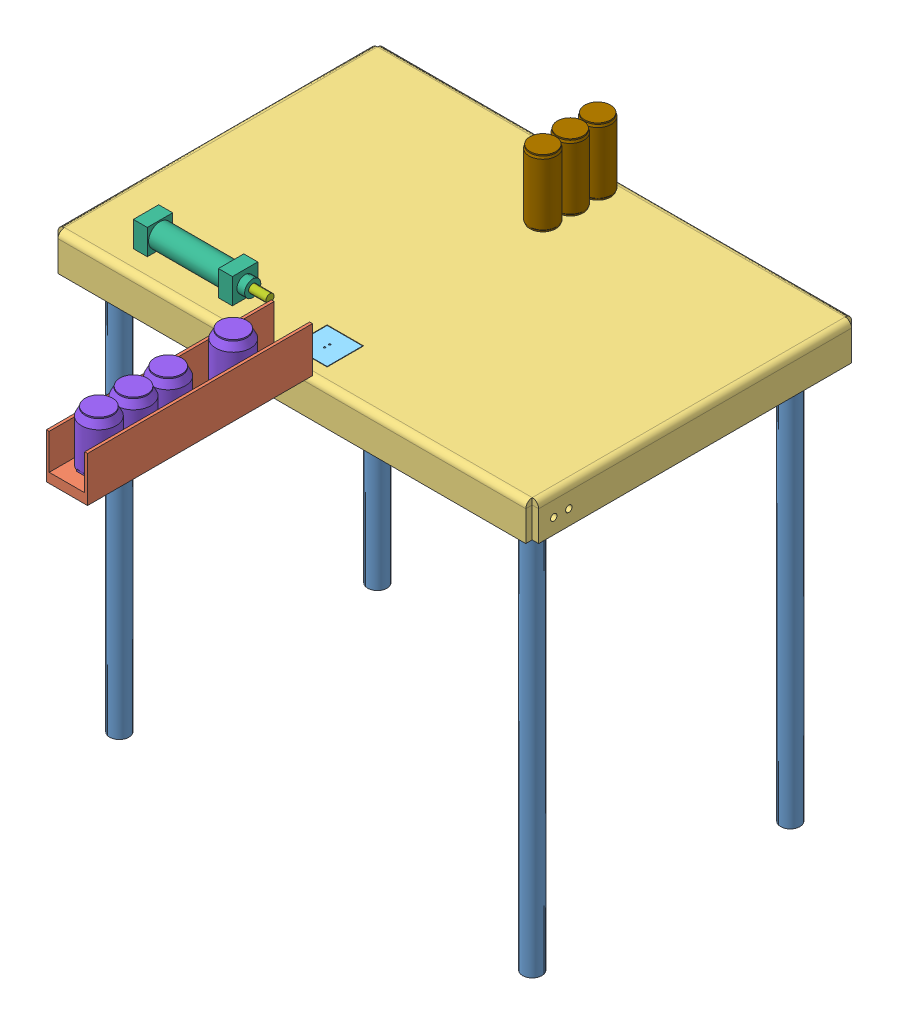
SolidWorks assembly Full_Assembly_v7, configuration Default. Lengths in mm.
Overall size (946.15 1042.06 1084.08).
19 component instances, 12 part files, 63 mates.
Components (placement in the parent):
- M37 Metal Table-1: M37 Metal Table [Default] at (-122.75 340.8931 1031.9817) size (914.4 863.6 609.6)
- Goose Output-1: Goose Output [Default] at (293.9688 417.0931 1047.8567) size (80.96 88.9 442.73)
- Table Topper-1: Table Topper [Default] at (-125.925 340.8931 1035.1567) size (946.15 72.1 641.35)
- Load Cell Assembly-1: Load Cell Assembly [Default] at (309.0555 358.077 899.7114) size (69.85 23.2 103.99)
  - Load Cell and Brace-1: Load Cell and Brace [Default] at (-9.1055 31.7162 92.7424) size (69 14.2 83)
  - scalePlate_v2_234-1: scalePlate_v2_234 [Default] at (-9.5305 54.9162 113.7283) x (0 0 -1) z (-1 0 0) size (69.85 9 69.85)
- Cylinder-1: Cylinder [Default] at (-22.0508 462.9931 953.5147) x (0 0 1) z (1 0 0) size (50 50 210)
- Rod-1: Rod [Default] at (221.9492 437.9931 978.5147) x (0 0.637822 -0.770184) z (0 0.770184 0.637822) size (16 134 16)
- can355mL-1: can355mL [Default] at (334.45 412.9931 1291.3582) x (0 0 -1) z (1 0 0) size (68.26 122.24 68.26)
- can355mL-2: can355mL [Default] at (334.45 412.9931 1427.8832) x (0 0 -1) z (1 0 0) size (68.26 122.24 68.26)
- can355mL-3: can355mL [Default] at (334.45 412.9931 1359.6207) x (0 0 -1) z (1 0 0) size (68.26 122.24 68.26)
- can250mL-1: can250mL [Default] at (334.45 412.9931 553.8493) x (-0.934308 0 -0.356465) z (0.356465 0 -0.934308) size (53.98 131.76 53.98)
- can250mL-2: can250mL [Default] at (334.45 412.9931 499.8743) x (0.439436 0 -0.898274) z (0.898274 0 0.439436) size (53.98 131.76 53.98)
- can250mL-3: can250mL [Default] at (334.45 412.9931 445.8993) x (0.515444 0 0.856923) z (-0.856923 0 0.515444) size (53.98 131.76 53.98)
- can355mL-7: can355mL [Default] at (334.45 412.9931 1163.3587) x (0 0 -1) z (1 0 0) size (68.26 122.24 68.26)
- AmpCase_Assembly_v1-1: AmpCase_Assembly_v1 [Default] at (378.0256 441.5889 898.6464) x (0 0 -1) z (-1 0 0) size (83 107 59)
  - AmpCase_LID_83x59x33_v1-1: AmpCase_LID_83x59x33_v1 [Default] at (42.2994 148.2958 -6.3457) x (1 0 0) z (0 0 -1) size (83 7 59)
  - AmpCase83x59x33_v1-1: AmpCase83x59x33_v1 [Default] at (42.2994 41.2958 52.6543) size (83 26 59)
- Solenoid_v1-1: Solenoid_v1 [Default] at (452.5858 378.2931 857.7853) size (118 22 83)
Mates (geometry in assembly coordinates):
- Width1: width aligned: plane of M37 Metal Table-1 through (791.65 366.2931 1031.9817) normal (1 0 0); plane of M37 Metal Table-1 through (-122.75 366.2931 1031.9817) normal (-1 0 0); plane of Table Topper-1 through (807.525 400.2931 1035.1567) normal (1 0 0); plane of Table Topper-1 through (-138.625 400.2931 1035.1567) normal (-1 0 0)
- Width2: width aligned: plane of M37 Metal Table-1 through (-122.75 366.2931 1031.9817) normal (0 0 1); plane of M37 Metal Table-1 through (-122.75 366.2931 422.3817) normal (0 0 -1); plane of Table Topper-1 through (-125.925 400.2931 1047.8567) normal (0 0 1); plane of Table Topper-1 through (-125.925 400.2931 406.5067) normal (0 0 -1)
- Distance1: distance = 863.6 mm aligned: plane of M37 Metal Table-1 through (-122.75 -446.5069 1031.9817) normal (0 -1 0); plane of Goose Output-1 through (374.9313 417.0931 1490.5914) normal (0 -1 0)
- LimitDistance1: limit distance = 432.5938 mm aligned: plane of Goose Output-1 through (374.9313 505.9931 1490.5914) normal (1 0 0); plane of Table Topper-1 through (807.525 400.2931 1035.1567) normal (1 0 0)
- LimitDistance2: limit distance = 432.5938 mm aligned: plane of Table Topper-1 through (-138.625 400.2931 1035.1567) normal (-1 0 0); plane of Goose Output-1 through (293.9688 417.0931 1490.5914) normal (-1 0 0)
- Parallel1: parallel aligned: plane of Goose Output-1 through (299.525 436.1431 1490.5914) normal (0 1 0); plane of Table Topper-1 through (-125.925 412.9931 1035.1567) normal (0 1 0)
- Coincident7: coincident aligned: plane of Table Topper-1 through (-125.925 412.9931 1035.1567) normal (0 1 0); plane of Load Cell Assembly-1/scalePlate_v2_234-1 through (299.525 412.9931 1013.4397) normal (0 1 0)
- Concentric1: concentric anti-aligned: cylinder of Cylinder-1 through (187.9492 437.9931 978.5147) axis (-1 0 0) radius 16; cylinder of Rod-1 through (87.9492 437.9931 978.5147) axis (1 0 0) radius 8
- LimitDistance3: limit distance = 34 mm aligned: plane of Rod-1 through (221.9492 437.9931 978.5147) normal (1 0 0); plane of Cylinder-1 through (187.9492 437.9931 978.5147) normal (1 0 0)
- Parallel2: parallel anti-aligned: plane of Table Topper-1 through (-125.925 400.2931 1047.8567) normal (0 0 1); plane of Cylinder-1 through (172.9492 462.9931 953.5147) normal (0 0 -1)
- Coincident9: coincident anti-aligned: plane of Table Topper-1 through (-125.925 412.9931 1035.1567) normal (0 1 0); plane of Cylinder-1 through (5.4492 412.9931 953.5147) normal (0 -1 0)
- Width3: width anti-aligned: plane of Goose Output-1 through (374.9313 505.9931 1490.5914) normal (1 0 0); plane of Goose Output-1 through (293.9688 417.0931 1490.5914) normal (-1 0 0); plane of Load Cell Assembly-1/scalePlate_v2_234-1 through (299.525 408.9931 1013.4397) normal (-1 0 0); plane of Load Cell Assembly-1/scalePlate_v2_234-1 through (369.375 408.9931 1013.4397) normal (1 0 0)
- Width4: width anti-aligned: plane of Cylinder-1 through (172.9492 462.9931 953.5147) normal (0 0 -1); plane of Cylinder-1 through (172.9492 462.9931 1003.5147) normal (0 0 1); plane of Load Cell Assembly-1/scalePlate_v2_234-1 through (299.525 408.9931 1013.4397) normal (0 0 1); plane of Load Cell Assembly-1/scalePlate_v2_234-1 through (299.525 408.9931 943.5897) normal (0 0 -1)
- Width5: width anti-aligned: plane of Table Topper-1 through (807.525 400.2931 1035.1567) normal (1 0 0); plane of Table Topper-1 through (-138.625 400.2931 1035.1567) normal (-1 0 0); plane of Load Cell Assembly-1/scalePlate_v2_234-1 through (299.525 408.9931 1013.4397) normal (-1 0 0); plane of Load Cell Assembly-1/scalePlate_v2_234-1 through (369.375 408.9931 1013.4397) normal (1 0 0)
- Coincident11: coincident anti-aligned: plane of Table Topper-1 through (-125.925 412.9931 1035.1567) normal (0 1 0); plane of can250mL-1 through (310.7186 412.9931 544.7951) normal (0 -1 0)
- Coincident18: coincident anti-aligned: plane of Table Topper-1 through (-125.925 412.9931 1035.1567) normal (0 1 0); plane of can355mL-2 through (334.45 412.9931 1400.8957) normal (0 -1 0)
- Coincident19: coincident anti-aligned: plane of Table Topper-1 through (-125.925 412.9931 1035.1567) normal (0 1 0); plane of can355mL-3 through (334.45 412.9931 1332.6332) normal (0 -1 0)
- Tangent5: tangent anti-aligned: cylinder of can355mL-2 through (334.45 412.9931 1427.8832) axis (0 -1 0) radius 34.1313; cylinder of can355mL-3 through (334.45 412.9931 1359.6207) axis (0 -1 0) radius 34.1313
- Width6: width: plane of Goose Output-1 through (299.525 505.9931 1490.5914) normal (1 0 0); plane of Goose Output-1 through (369.375 436.1431 1490.5914) normal (-1 0 0); cylinder of can250mL-1 through (334.45 412.9931 553.8493) axis (0 -1 0) radius 26.9875
- Width8: width: plane of Goose Output-1 through (369.375 436.1431 1490.5914) normal (-1 0 0); plane of Goose Output-1 through (299.525 505.9931 1490.5914) normal (1 0 0); cylinder of can355mL-2 through (334.45 412.9931 1427.8832) axis (0 -1 0) radius 34.1313
- Width10: width: plane of Goose Output-1 through (299.525 505.9931 1490.5914) normal (1 0 0); plane of Goose Output-1 through (369.375 436.1431 1490.5914) normal (-1 0 0); cylinder of can355mL-3 through (334.45 412.9931 1359.6207) axis (0 -1 0) radius 34.1313
- Coincident20: coincident anti-aligned: plane of Table Topper-1 through (-125.925 412.9931 1035.1567) normal (0 1 0); plane of can250mL-2 through (345.6117 412.9931 477.0581) normal (0 -1 0)
- Coincident21: coincident anti-aligned: plane of Table Topper-1 through (-125.925 412.9931 1035.1567) normal (0 1 0); plane of can250mL-3 through (347.5423 412.9931 467.6651) normal (0 -1 0)
- Tangent6: tangent anti-aligned: cylinder of can250mL-1 through (334.45 412.9931 553.8493) axis (0 -1 0) radius 26.9875; cylinder of can250mL-2 through (334.45 412.9931 499.8743) axis (0 -1 0) radius 26.9875
- Tangent7: tangent anti-aligned: cylinder of can250mL-2 through (334.45 412.9931 499.8743) axis (0 -1 0) radius 26.9875; cylinder of can250mL-3 through (334.45 412.9931 445.8993) axis (0 -1 0) radius 26.9875
- Width11: width: plane of Goose Output-1 through (299.525 505.9931 1490.5914) normal (1 0 0); plane of Goose Output-1 through (369.375 436.1431 1490.5914) normal (-1 0 0); cylinder of can250mL-2 through (334.45 412.9931 499.8743) axis (0 -1 0) radius 26.9875
- Width12: width: plane of Goose Output-1 through (299.525 505.9931 1490.5914) normal (1 0 0); plane of Goose Output-1 through (369.375 436.1431 1490.5914) normal (-1 0 0); cylinder of can250mL-3 through (334.45 412.9931 445.8993) axis (0 -1 0) radius 26.9875
- Coincident22: coincident anti-aligned: plane of Goose Output-1 through (293.9688 417.0931 1047.8567) normal (0 0 -1); plane of Table Topper-1 through (-125.925 400.2931 1047.8567) normal (0 0 1)
- Width14: width aligned: plane of Table Topper-1 through (370.391 340.8931 1014.4557) normal (-1 0 0); plane of Load Cell Assembly-1/scalePlate_v2_234-1 through (298.509 340.8931 1014.4557) normal (1 0 0); plane of Table Topper-1 through (299.525 408.9931 1013.4397) normal (-1 0 0); plane of Load Cell Assembly-1/scalePlate_v2_234-1 through (369.375 408.9931 1013.4397) normal (1 0 0)
- Width15: width anti-aligned: plane of Table Topper-1 through (298.509 340.8931 1014.4557) normal (0 0 -1); plane of Load Cell Assembly-1/scalePlate_v2_234-1 through (298.509 340.8931 942.5737) normal (0 0 1); plane of Table Topper-1 through (299.525 408.9931 1013.4397) normal (0 0 1); plane of Load Cell Assembly-1/scalePlate_v2_234-1 through (299.525 408.9931 943.5897) normal (0 0 -1)
- Width17: width: plane of Goose Output-1 through (369.375 436.1431 1490.5914) normal (-1 0 0); plane of can355mL-4 through (299.525 505.9931 1490.5914) normal (1 0 0); cylinder of Goose Output-1 through (334.45 436.1431 1259.8293) axis (0 -1 0) radius 34.1313
- Coincident31: coincident anti-aligned: plane of Table Topper-1 through (-125.925 412.9931 1035.1567) normal (0 1 0); plane of can355mL-7 through (334.45 412.9931 1136.3712) normal (0 -1 0)
- Width19: width: plane of Goose Output-1 through (369.375 436.1431 1490.5914) normal (-1 0 0); plane of can355mL-7 through (299.525 505.9931 1490.5914) normal (1 0 0); cylinder of Goose Output-1 through (334.45 412.9931 1163.3587) axis (0 -1 0) radius 34.1313
- Coincident33: coincident anti-aligned: plane of Table Topper-1 through (-125.925 412.9931 1035.1567) normal (0 1 0); plane of can355mL-1 through (334.45 412.9931 1264.3707) normal (0 -1 0)
- Tangent13: tangent anti-aligned: cylinder of can355mL-1 through (334.45 412.9931 1291.3582) axis (0 -1 0) radius 34.1313; cylinder of can355mL-3 through (334.45 412.9931 1359.6207) axis (0 -1 0) radius 34.1313
- Width20: width: plane of Goose Output-1 through (299.525 505.9931 1490.5914) normal (1 0 0); plane of can355mL-1 through (369.375 436.1431 1490.5914) normal (-1 0 0); cylinder of Goose Output-1 through (334.45 412.9931 1291.3582) axis (0 -1 0) radius 34.1313
- Parallel4: parallel aligned: plane of M37 Metal Table-1 through (-122.75 366.2931 1031.9817) normal (0 0 1); plane of can355mL-7 through (334.45 412.9931 1197.4899) normal (0 0 1)
- Parallel5: parallel aligned: plane of M37 Metal Table-1 through (-122.75 366.2931 1031.9817) normal (0 0 1); plane of can355mL-2 through (334.45 412.9931 1462.0144) normal (0 0 1)
- Parallel6: parallel aligned: plane of M37 Metal Table-1 through (-122.75 366.2931 1031.9817) normal (0 0 1); plane of can355mL-3 through (334.45 412.9931 1393.7519) normal (0 0 1)
- Parallel7: parallel aligned: plane of M37 Metal Table-1 through (-122.75 366.2931 1031.9817) normal (0 0 1); plane of can355mL-1 through (334.45 412.9931 1325.4894) normal (0 0 1)
- LimitDistance14: limit distance = 127.9995 mm aligned: plane of can355mL-7 through (334.45 412.9931 1197.4899) normal (0 0 1); plane of can355mL-1 through (334.45 412.9931 1325.4894) normal (0 0 1)
- Tangent14: tangent anti-aligned: cylinder of can355mL-9 through (334.45 412.9931 1319.9352) axis (0 -1 0) radius 34.1313; cylinder of can355mL-10 through (334.45 412.9931 1388.1977) axis (0 -1 0) radius 34.1313
- Tangent15: tangent anti-aligned: cylinder of can355mL-8 through (334.45 412.9931 1456.4602) axis (0 -1 0) radius 34.1313; cylinder of can355mL-10 through (334.45 412.9931 1388.1977) axis (0 -1 0) radius 34.1313
- Coincident38: coincident anti-aligned: plane of Table Topper-1 through (-125.925 412.9931 1035.1567) normal (0 1 0); plane of can355mL-8 through (334.45 412.9931 1429.4727) normal (0 -1 0)
- Coincident39: coincident aligned: plane of can355mL-9 through (334.45 412.9931 1292.9477) normal (0 -1 0); plane of can355mL-10 through (334.45 412.9931 1361.2102) normal (0 -1 0)
- Coincident40: coincident anti-aligned: plane of Table Topper-1 through (-125.925 412.9931 1035.1567) normal (0 1 0); plane of can355mL-10 through (334.45 412.9931 1361.2102) normal (0 -1 0)
- Width21: width: plane of Goose Output-1 through (299.525 505.9931 1490.5914) normal (1 0 0); plane of Goose Output-1 through (369.375 436.1431 1490.5914) normal (-1 0 0); cylinder of can355mL-8 through (334.45 412.9931 1456.4602) axis (0 -1 0) radius 34.1313
- Width22: width: plane of Goose Output-1 through (374.9313 505.9931 1490.5914) normal (1 0 0); plane of Goose Output-1 through (293.9688 417.0931 1490.5914) normal (-1 0 0); cylinder of can355mL-10 through (334.45 412.9931 1388.1977) axis (0 -1 0) radius 34.1313
- Width23: width: plane of Goose Output-1 through (374.9313 505.9931 1490.5914) normal (1 0 0); plane of Goose Output-1 through (293.9688 417.0931 1490.5914) normal (-1 0 0); cylinder of can355mL-9 through (334.45 412.9931 1319.9352) axis (0 -1 0) radius 34.1313
- LimitDistance15: limit distance = 98.6078 mm aligned: plane of can355mL-9 through (334.45 412.9931 1354.0664) normal (0 0 1); plane of can355mL-2 through (334.45 412.9931 1462.0144) normal (0 0 1)
- Parallel8: parallel aligned: plane of M37 Metal Table-1 through (-122.75 366.2931 1031.9817) normal (0 0 1); plane of can355mL-8 through (334.45 412.9931 1490.5914) normal (0 0 1)
- Parallel10: parallel aligned: plane of M37 Metal Table-1 through (-122.75 366.2931 1031.9817) normal (0 0 1); plane of can355mL-10 through (334.45 412.9931 1422.3289) normal (0 0 1)
- LimitDistance16: limit distance = 0 mm aligned: plane of can355mL-8 through (334.45 412.9931 1490.5914) normal (0 0 1); plane of Goose Output-1 through (293.9688 417.0931 1490.5914) normal (0 0 1)
- Parallel12: parallel aligned: plane of M37 Metal Table-1 through (-122.75 366.2931 1031.9817) normal (0 0 1); plane of can355mL-11 through (334.45 412.9931 1012.7539) normal (0 0 1)
- LimitDistance18: limit distance = 68.2625 mm aligned: plane of can355mL-11 through (334.45 412.9931 1012.7539) normal (0 0 1); plane of can355mL-7 through (334.45 412.9931 1197.4899) normal (0 0 1)
- PathMate3: path: point of can355mL-11
- Parallel13: parallel anti-aligned: plane of Table Topper-1 through (-125.925 412.9931 1035.1567) normal (0 1 0); plane of can355mL-11 through (334.45 412.9931 951.6352) normal (0 -1 0)
- Parallel14: parallel aligned: plane of M37 Metal Table-1 through (-122.75 366.2931 1031.9817) normal (0 0 1); plane of can355mL-11 through (334.45 412.9931 1012.7539) normal (0 0 1)
- Coincident41: coincident aligned: plane of M37 Metal Table-1 through (-122.75 340.8931 1031.9817) normal (0 -1 0); plane of Table Topper-1 through (-125.925 340.8931 1035.1567) normal (0 -1 0)
- Coincident42: coincident anti-aligned: plane of Table Topper-1 through (-125.925 400.2931 1035.1567) normal (0 -1 0); plane of AmpCase_Assembly_v1-1/AmpCase83x59x33_v1-1 through (325.3712 400.2931 856.347) normal (0 1 0)
- Parallel15: parallel aligned: plane of M37 Metal Table-1 through (-122.75 366.2931 1031.9817) normal (0 0 1); plane of AmpCase_Assembly_v1-1/AmpCase83x59x33_v1-1 through (325.3712 397.2931 856.347) normal (0 0 1)
- Parallel16: parallel aligned: plane of M37 Metal Table-1 through (-122.75 366.2931 1031.9817) normal (0 0 1); plane of Solenoid_v1-1 through (452.5858 400.2931 857.7853) normal (0 0 1)
- Coincident45: coincident aligned: plane of AmpCase_Assembly_v1-1/AmpCase83x59x33_v1-1 through (325.3712 400.2931 856.347) normal (0 1 0); plane of Solenoid_v1-1 through (452.5858 400.2931 857.7853) normal (0 1 0)
